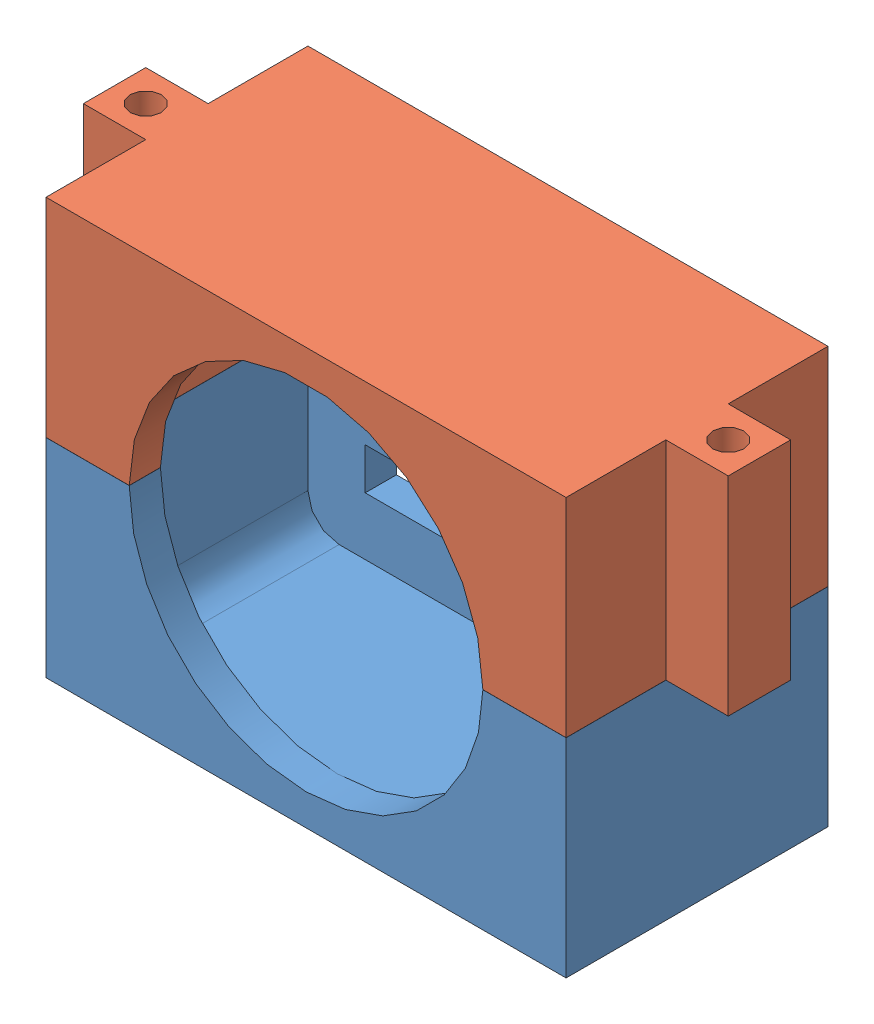
SolidWorks assembly Assem1, configuration Default. Lengths in mm.
Overall size (62 40.01 29.18).
2 component instances, 2 part files, 2 mates.
Components (placement in the parent):
- camera_mount_bottom-1: camera_mount_bottom [Default] at (21.84 18.831 34.8428) size (54 20 29.18)
- camera_mount_top-1: camera_mount_top [Default] at (21.84 38.8398 34.8428) size (62 20 25.18)
Mates (geometry in assembly coordinates):
- Coincident1: coincident aligned: plane of camera_mount_bottom-1 through (-3.16 38.831 22.2528) normal (0 0 -1); plane of camera_mount_top-1 through (-3.16 58.8398 22.2528) normal (0 0 -1)
- Coincident2: coincident aligned: plane of camera_mount_bottom-1 through (-3.16 38.831 47.4328) normal (-1 0 0); plane of camera_mount_top-1 through (-3.16 58.8398 47.4328) normal (-1 0 0)
